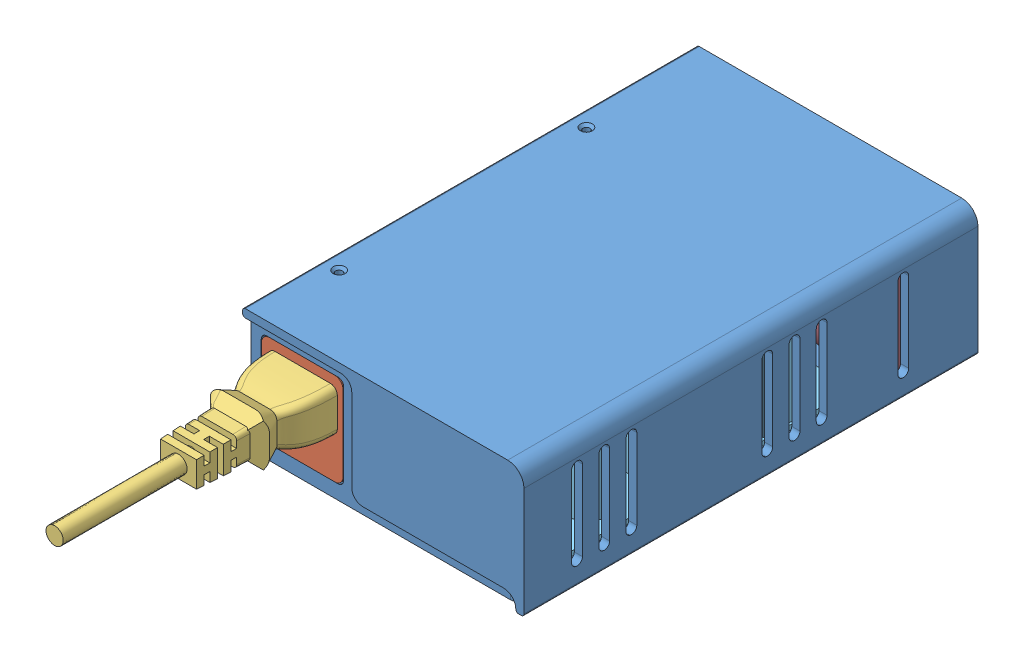
SolidWorks assembly Portable Power Supply Assembly, configuration Default. Lengths in mm.
Overall size (106.17 47.59 265.29).
18 component instances, 14 part files, 39 mates.
Components (placement in the parent):
- Frame-1: Frame [Default] at (-8.5 0 -2) x (-1 0 0) z (0 0 -1) size (103.5 47 167)
- 6200.4125-1: 6200.4125 [Default] at (-40.8183 0.75 158) x (-1 0 0) z (0 0 -1) size (30 34 28.5)
- IEC 320 C13 Cable End-1: IEC 320 C13 Cable End [Default] at (-40.6117 6.4066 144.744) x (1 0 0) z (0 -1 0) size (28.88 110.34 18.89)
- adjustable-step-down-voltage-regulator-d24v3ax-d24v6ax-d36v6ax-1: adjustable-step-down-voltage-regulator-d24v3ax-d24v6ax-d36v6ax [Default] at (-28.84 -16.2 73.75) x (-1 0 0) z (0 -1 0) size (10.16 15.24 3.73)
- 110 and 220 to 36v 5A converter-1: 110 and 220 to 36v 5A converter [Default] at (-0.4058 -15 109.1272) x (0 0 -1) z (1 0 0) size (115 35.75 66)
- NF-A4x10 Fan-1: NF-A4x10 Fan [Default] at (-43.5058 0.0655 66.0655) x (0 0 1) z (0 1 0) size (40.14 12 40.18)
  - NF-A4x10_Noctua_40mm.step-1: NF-A4x10_Noctua_40mm.step [Default] at origin size (40.14 12 40.18)
    - Noctua-NF-A4x10 v1.step-1: Noctua-NF-A4x10 v1.step [Default] at (0 -5.2451 0) x (1 0 0) z (0 -1 0) size (40.14 40.18 12)
    - Noctua nf-a8-pwm fan 80x80x25 v2.step-1: Noctua nf-a8-pwm fan 80x80x25 v2.step [Default] at (0 -0.546 0) x (1 0 0) z (0 -1 0) size (36.32 36.48 8.8)
- Pololu holder-1: Pololu holder [Default] at (-33.75 -20 66) x (0 0 1) z (-1 0 0) size (25.5 4.8 12)
- Amass XT60E1-M -1: Amass XT60E1-M  [Default] at (-56.75 0 39.25) x (0 -1 0) z (0 0 1) size (27.1 16.8 12.1)
- KCD2-203N-1: KCD2-203N [Default] at (-57.75 0 112.9) x (0 0 1) z (-1 0 0) size (25.3 35 31.17)
- Amass XT60E1-M -2: Amass XT60E1-M  [Default] at (-56.75 0 92.75) x (0 -1 0) z (0 0 1) size (27.1 16.8 12.1)
- CT2240-0-1: CT2240-0 [Default] at (-48.25 10.75 -2.8) x (0 1 0) z (-1 0 0) size (14.2 28.4 14.2)
- CT2240-2-1: CT2240-2 [Default] at (-48.25 -10.75 -2.8) x (0 -1 0) z (1 0 0) size (14.2 28.4 14.2)
- DSP5005-1: DSP5005 [Default] at (25.0749 -17.8023 -2) x (-1 0 0) z (0 1 0) size (79.5 48.5 43)
- Rubber Foot-1: Rubber Foot [Default] at (-9.7523 -23.0875 13.6988) size (85 1.59 12)
- Rubber Foot-2: Rubber Foot [Default] at (-9.7523 -23.0875 143.6988) size (85 1.59 12)
Mates (geometry in assembly coordinates):
- Symmetric1: symmetric aligned: plane of DSP5005-1 through (35.85 -19.4 22.6) normal (1 0 0); plane of DSP5005-1 through (-35.85 -19.4 22.6) normal (-1 0 0)
- Symmetric3: symmetric aligned: plane of DSP5005-1 through (35.85 -19.4 22.6) normal (0 -1 0); plane of DSP5005-1 through (35.85 19.4 22.6) normal (0 1 0); plane of assembly through (0 0 0) normal (0 1 0)
- Coincident4: coincident aligned: plane of DSP5005-1 through (25.0749 -17.8023 0) normal (0 0 1)
- Width2: width anti-aligned: plane of Frame-1 through (-36 -20 6) normal (1 0 0); plane of Frame-1 through (36 -20 6) normal (-1 0 0); plane of DSP5005-1 through (-35.85 -19.4 22.6) normal (-1 0 0); plane of DSP5005-1 through (35.85 -19.4 22.6) normal (1 0 0)
- Width3: width anti-aligned: plane of Frame-1 through (-36 -20 6) normal (0 1 0); plane of Frame-1 through (-36 20 6) normal (0 -1 0); plane of DSP5005-1 through (35.85 -19.4 22.6) normal (0 -1 0); plane of DSP5005-1 through (35.85 19.4 22.6) normal (0 1 0)
- Coincident12: coincident anti-aligned: plane of DSP5005-1 through (25.0749 -17.8023 0) normal (0 0 1); plane of Frame-1 through (-8.5 0 0) normal (0 0 -1)
- Width5: width anti-aligned: plane of Frame-1 through (-8.5 -15.25 154.5) normal (0 1 0); plane of Frame-1 through (-8.5 16.75 154.5) normal (0 -1 0); plane of 6200.4125-1 through (-27.0683 -15 132.5) normal (0 -1 0); plane of 6200.4125-1 through (-27.0683 16.5 132.5) normal (0 1 0)
- Width6: width anti-aligned: plane of KCD2-203N-1 through (-41.75 12.75 123.4) normal (0 0 1); plane of KCD2-203N-1 through (-41.75 12.75 102.4) normal (0 0 -1); plane of Frame-1 through (-54.75 -14.5 123.9) normal (0 0 -1); plane of Frame-1 through (-54.75 -14.5 101.9) normal (0 0 1)
- Width7: width anti-aligned: plane of Frame-1 through (-54.75 -14.5 101.9) normal (0 1 0); plane of Frame-1 through (-54.75 14.5 101.9) normal (0 -1 0); plane of KCD2-203N-1 through (-41.75 -12.75 102.4) normal (0 -1 0); plane of KCD2-203N-1 through (-41.75 12.75 102.4) normal (0 1 0)
- Coincident14: coincident anti-aligned: plane of KCD2-203N-1 through (-57.75 0 112.9) normal (1 0 0); plane of Frame-1 through (-57.75 0 -2) normal (-1 0 0)
- Coincident15: coincident anti-aligned: plane of Amass XT60E1-M -2 through (-56.75 0 92.75) normal (-1 0 0); plane of Frame-1 through (-56.75 21.5 6) normal (1 0 0)
- Concentric3: concentric anti-aligned: cylinder of Amass XT60E1-M -1 through (-56.75 10.25 39.25) axis (1 0 0) radius 1.25; cylinder of Frame-1 through (-54.75 10.25 39.25) axis (-1 0 0) radius 1.35
- Concentric4: concentric anti-aligned: cylinder of Amass XT60E1-M -1 through (-56.75 -10.25 39.25) axis (1 0 0) radius 1.25; cylinder of Frame-1 through (-54.75 -10.25 39.25) axis (-1 0 0) radius 1.35
- Coincident16: coincident anti-aligned: plane of Amass XT60E1-M -1 through (-56.75 0 39.25) normal (-1 0 0); plane of Frame-1 through (-56.75 21.5 6) normal (1 0 0)
- Concentric5: concentric anti-aligned: cylinder of NF-A4x10 Fan-1/NF-A4x10_Noctua_40mm.step-1/Noctua-NF-A4x10 v1.step-1 through (-54.25 -16 50) axis (1 0 0) radius 2.159; cylinder of Frame-1 through (-52.75 -16 50) axis (-1 0 0) radius 1.25
- Coincident17: coincident anti-aligned: plane of NF-A4x10 Fan-1/NF-A4x10_Noctua_40mm.step-1/Noctua-NF-A4x10 v1.step-1 through (-54.75 -17.9624 48.0376) normal (-1 0 0); plane of Frame-1 through (-54.75 0 -2) normal (1 0 0)
- Concentric6: concentric anti-aligned: cylinder of CT2240-0-1 through (-48.25 10.75 18.9101) axis (0 0 1) radius 6; cylinder of Frame-1 through (-48.25 10.75 6) axis (0 0 -1) radius 6.25
- Parallel2: parallel aligned: plane of CT2240-0-1 through (-53.6 26.419 -35.8622) normal (-1 0 0); plane of Frame-1 through (-42.75 13.7186 6) normal (-1 0 0)
- Coincident20: coincident anti-aligned: plane of CT2240-0-1 through (-48.25 16.75 0) normal (0 0 1); plane of Frame-1 through (-48.25 10.75 0) normal (0 0 -1)
- Concentric7: concentric anti-aligned: cylinder of CT2240-2-1 through (-48.25 -10.75 18.9101) axis (0 0 1) radius 6; cylinder of Frame-1 through (-48.25 -10.75 6) axis (0 0 -1) radius 6.25
- Coincident21: coincident anti-aligned: plane of CT2240-2-1 through (-48.25 -16.75 0) normal (0 0 1); plane of Frame-1 through (-48.25 -10.75 0) normal (0 0 -1)
- Parallel3: parallel anti-aligned: plane of CT2240-2-1 through (-42.9 -26.419 -35.8622) normal (1 0 0); plane of Frame-1 through (-42.75 -13.7186 6) normal (-1 0 0)
- Coincident23: coincident: plane of 110 and 220 to 36v 5A converter-1 through (39.75 -13.25 153.5) normal (1 0 0); line of DSP5005-1 through (39.75 -18.5 -2) axis (0 1 0)
- Coincident25: coincident anti-aligned: plane of 110 and 220 to 36v 5A converter-1 through (-0.4058 -15 109.1272) normal (0 -1 0); plane of Frame-1 through (34.75 -15 148.5) normal (0 1 0)
- Concentric8: concentric anti-aligned: cylinder of 110 and 220 to 36v 5A converter-1 through (34.75 -15 148.5) axis (0 1 0) radius 2; cylinder of Frame-1 through (34.75 -15 148.5) axis (0 -1 0) radius 1.25
- Coincident26: coincident aligned: plane of 6200.4125-1 through (-40.8183 0.75 161) normal (0 0 1); plane of Frame-1 through (-54.75 -21.5 161) normal (0 0 1)
- Coincident27: coincident anti-aligned: plane of adjustable-step-down-voltage-regulator-d24v3ax-d24v6ax-d36v6ax-1 through (-28.84 -16.2 73.75) normal (0 1 0); plane of Pololu holder-1 through (-29.75 -16.2 58.25) normal (0 -1 0)
- Coincident28: coincident anti-aligned: plane of adjustable-step-down-voltage-regulator-d24v3ax-d24v6ax-d36v6ax-1 through (-39 -17.216 73.75) normal (-1 0 0); plane of Pololu holder-1 through (-39 -16.2 58.25) normal (1 0 0)
- Coincident29: coincident anti-aligned: plane of adjustable-step-down-voltage-regulator-d24v3ax-d24v6ax-d36v6ax-1 through (-28.84 -17.216 73.75) normal (0 0 1); plane of Pololu holder-1 through (-39 -16.2 73.75) normal (0 0 -1)
- Concentric12: concentric anti-aligned: cylinder of Frame-1 through (-33.75 -21.5 76.25) axis (0 1 0) radius 1.25; cylinder of Pololu holder-1 through (-33.75 -16.2 76.25) axis (0 -1 0) radius 0.8
- Concentric13: concentric anti-aligned: cylinder of Frame-1 through (-33.75 -21.5 55.75) axis (0 1 0) radius 1.25; cylinder of Pololu holder-1 through (-33.75 -16.2 55.75) axis (0 -1 0) radius 0.8
- Coincident31: coincident: plane of Frame-1 through (-36 -20 6) normal (0 1 0); line of Pololu holder-1 through (-28.5162 -20 56.6759) axis (-0.787041 0 -0.616901)
- Concentric14: concentric anti-aligned: cylinder of Amass XT60E1-M -2 through (-56.75 -10.25 92.75) axis (1 0 0) radius 1.25; cylinder of Frame-1 through (-54.75 -10.25 92.75) axis (-1 0 0) radius 1.35
- Concentric15: concentric anti-aligned: cylinder of Amass XT60E1-M -2 through (-56.75 10.25 92.75) axis (1 0 0) radius 1.25; cylinder of Frame-1 through (-54.75 10.25 92.75) axis (-1 0 0) radius 1.35
- Coincident34: coincident anti-aligned: plane of Frame-1 through (-56.75 -21.5 6) normal (0 -1 0); plane of Rubber Foot-1 through (-9.7523 -21.5 13.6988) normal (0 1 0)
- Coincident35: coincident aligned: plane of Full Power supply assembly-1/Rubber feet-4 through (211.059 -23.0875 37.5852) normal (0 -1 0); plane of Rubber Foot-1 through (-9.7523 -23.0875 13.6988) normal (0 -1 0)
- Distance1: distance = 7.4977 mm aligned: plane of Rubber Foot-1 through (-52.2523 -21.5 19.6988) normal (-1 0 0); plane of Frame-1 through (-59.75 21.5 6) normal (-1 0 0)
- Parallel5: parallel anti-aligned: plane of Full Power supply assembly-1/Power supply lid-1 through (211.7741 32.8125 162.5534) normal (1 0 0); plane of Frame-1 through (-59.75 21.5 6) normal (-1 0 0)
- Coincident38: coincident anti-aligned: plane of 6200.4125-1 through (-40.8183 0.75 161) normal (0 0 1); plane of IEC 320 C13 Cable End-1 through (-27.9117 -1.5182 161) normal (0 0 -1)
